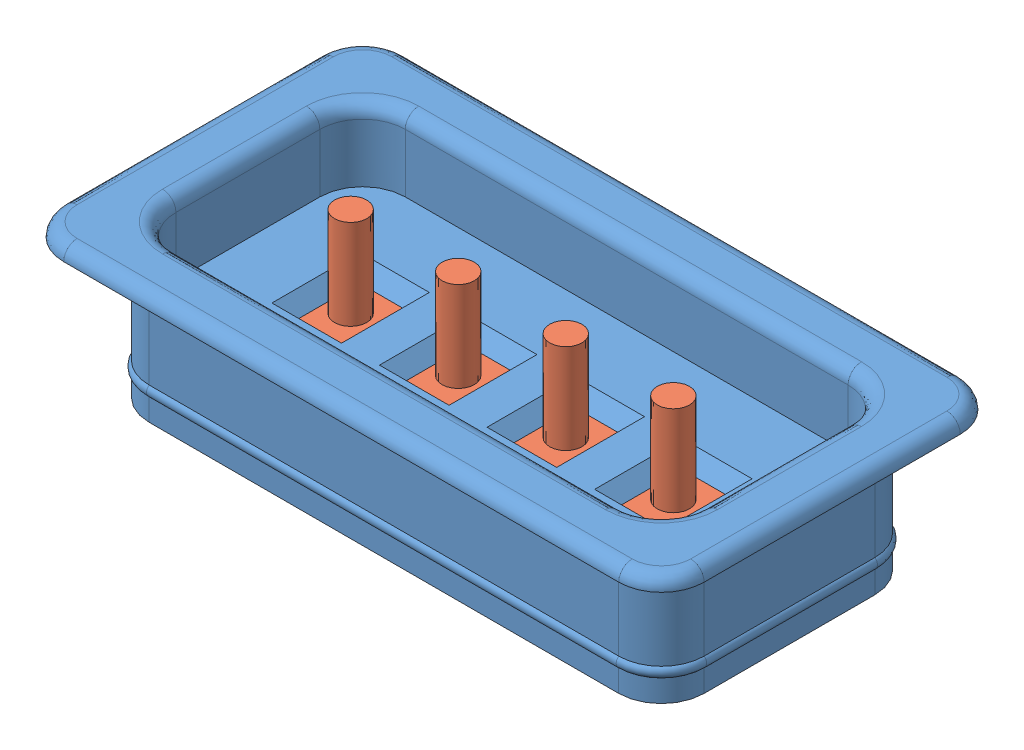
SolidWorks assembly Switch Assembly, configuration Default. Lengths in mm.
Overall size (95.25 28.83 50.8).
6 component instances, 3 part files, 18 mates.
Components (placement in the parent):
- switch plate-1: switch plate [Default] x (-1 0 0) z (0 0 1) size (95.25 27.76 50.8)
- Switch-1: Switch [Default] at (-24 -22.6822 0) x (0 0 1) z (-1 0 0) size (23.1 28.83 10.83)
- Switch-2: Switch [Default] at (-8 -22.6822 0) x (0 0 1) z (-1 0 0) size (23.1 28.83 10.83)
- Switch-3: Switch [Default] at (8 -22.6822 0) x (0 0 1) z (-1 0 0) size (23.1 28.83 10.83)
- Switch-4: Switch [Default] at (24 -22.6822 0) x (0 0 1) z (-1 0 0) size (23.1 28.83 10.83)
- PCB-1: PCB [Default] at (0 -26.37 0) size (64 1.6 28)
Mates (geometry in assembly coordinates):
- Coincident1: coincident anti-aligned: plane of switch plate-1 through (0 0 0) normal (0 -1 0)
- Coincident2: coincident anti-aligned: plane of switch plate-1 through (0 0 0) normal (-1 0 0)
- Coincident3: coincident aligned: plane of switch plate-1 through (0 0 0) normal (0 0 1)
- Coincident4: coincident anti-aligned: plane of Switch-1 through (-24 -12.7 0) normal (0 1 0); plane of switch plate-1 through (0 -12.7 0) normal (0 -1 0)
- Coincident6: coincident aligned: plane of Switch-1 through (-24 -22.6822 0) normal (0 0 1); plane of switch plate-1 through (0 0 0) normal (0 0 1)
- Coincident7: coincident: point of Switch-1; moEndPointRef_w of switch plate-1
- Coincident8: coincident aligned: plane of Switch-3 through (8 -12.7 0) normal (0 1 0); plane of Switch-4 through (24 -12.7 0) normal (0 1 0)
- Coincident9: coincident aligned: plane of Switch-2 through (-8 -12.7 0) normal (0 1 0); plane of Switch-3 through (8 -12.7 0) normal (0 1 0)
- Coincident10: coincident anti-aligned: plane of switch plate-1 through (0 -12.7 0) normal (0 -1 0); plane of Switch-2 through (-8 -12.7 0) normal (0 1 0)
- Coincident11: coincident aligned: plane of Switch-1 through (-18.5835 -12.7 11.55) normal (0 0 1); plane of Switch-2 through (-2.5835 -12.7 11.55) normal (0 0 1)
- Coincident12: coincident aligned: plane of Switch-1 through (-18.5835 -12.7 11.55) normal (0 0 1); plane of Switch-3 through (13.4165 -12.7 11.55) normal (0 0 1)
- Coincident13: coincident aligned: plane of Switch-3 through (13.4165 -12.7 11.55) normal (0 0 1); plane of Switch-4 through (29.4166 -12.7 11.55) normal (0 0 1)
- Coincident14: coincident: unknown of switch plate-1; plane of Switch-4 through (24 -22.6822 0) normal (-1 0 0)
- Coincident15: coincident: unknown of switch plate-1; plane of Switch-3 through (8 -22.6822 0) normal (-1 0 0)
- Coincident16: coincident: unknown of switch plate-1; plane of Switch-2 through (-8 -22.6822 0) normal (-1 0 0)
- Coincident17: coincident aligned: plane of PCB-1 through (0 -26.37 0) normal (1 0 0)
- Coincident18: coincident aligned: plane of PCB-1 through (0 -26.37 0) normal (0 0 1)
- Coincident19: coincident anti-aligned: plane of PCB-1 through (0 -24.77 0) normal (0 1 0); plane of Switch-4 through (18.5835 -24.77 -11.55) normal (0 -1 0)
